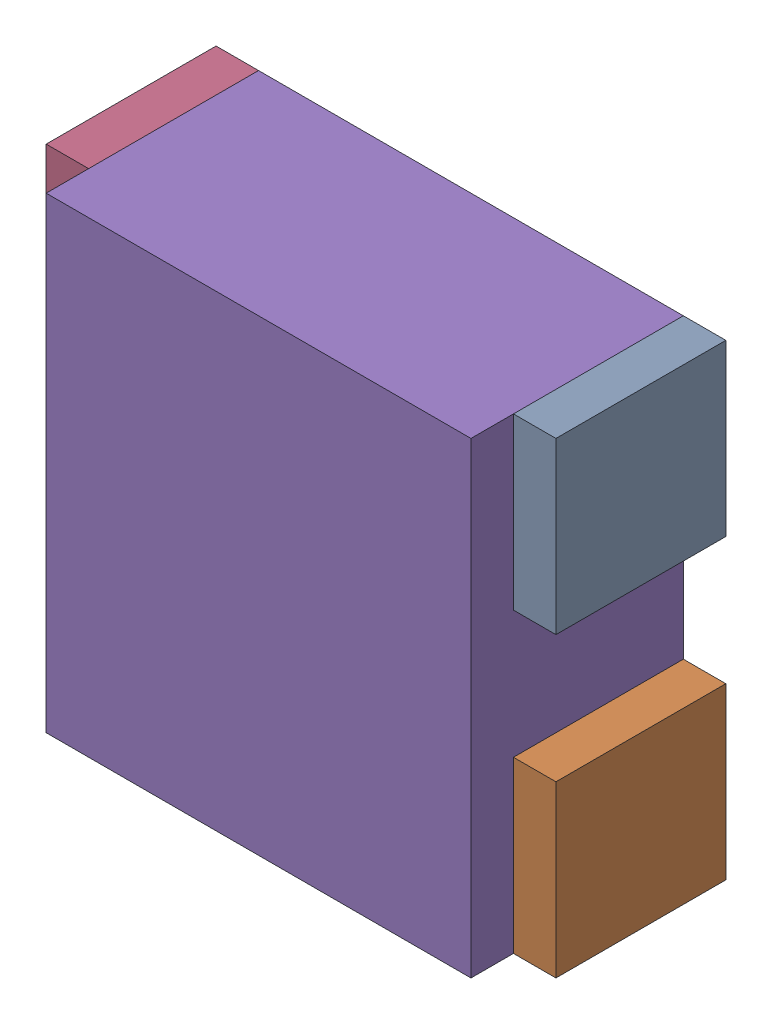
SolidWorks assembly RN10, configuration Default. Lengths in mm.
Overall size (1.2 1.1 0.5).
10 component instances, 2 part files, 0 mates.
Components (placement in the parent):
- 791587232-1: 791587232 [Default] at (111.15 52.75 0) size (0.1 0.4 0.4)
  - Extruded_10-1: Extruded_10 [Default] at origin size (0.1 0.4 0.4)
- 791587232-2: 791587232 [Default] at (111.15 52.05 0) size (0.1 0.4 0.4)
  - Extruded_10-1: Extruded_10 [Default] at origin size (0.1 0.4 0.4)
- 791587232-3: 791587232 [Default] at (110.05 52.05 0) size (0.1 0.4 0.4)
  - Extruded_10-1: Extruded_10 [Default] at origin size (0.1 0.4 0.4)
- 791587232-4: 791587232 [Default] at (110.05 52.75 0) size (0.1 0.4 0.4)
  - Extruded_10-1: Extruded_10 [Default] at origin size (0.1 0.4 0.4)
- 836749552-1: 836749552 [Default] at (110.6 52.4 0) size (1 1.1 0.5)
  - Extruded_11-1: Extruded_11 [Default] at origin size (1 1.1 0.5)
